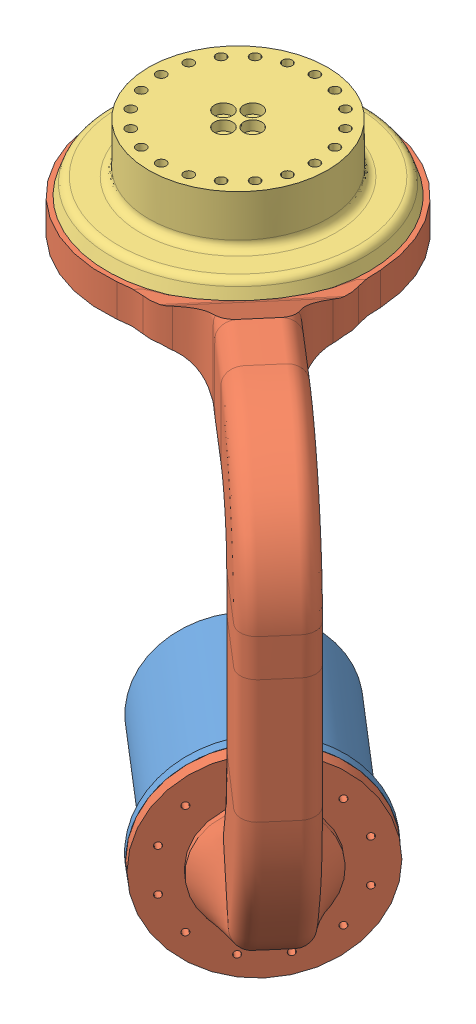
SolidWorks assembly Wheel rod, configuration Default. Lengths in mm.
Overall size (177.47 175.42 169.09).
5 component instances, 4 part files, 0 mates.
Components (placement in the parent):
- wheelsupportv2.iam-1: wheelsupportv2.iam [Default] at origin size (177.47 175.42 169.09)
  - Component22.ipt-1: Component22.ipt [Default] at (97.5935 0 36.1716) x (-0.758442 0 -0.65174) z (0.65174 0 -0.758442) size (57 60 60)
  - Component24.ipt-1: Component24.ipt [Default] at (97.5935 0 36.1716) x (-0.758442 0 -0.65174) z (0.65174 0 -0.758442) size (162.16 166.67 83.6)
  - Component27.ipt-1: Component27.ipt [Default] at origin size (80.57 22.5 80.57)
  - Component28.ipt-1: Component28.ipt [Default] at origin size (70.49 10 70.49)
